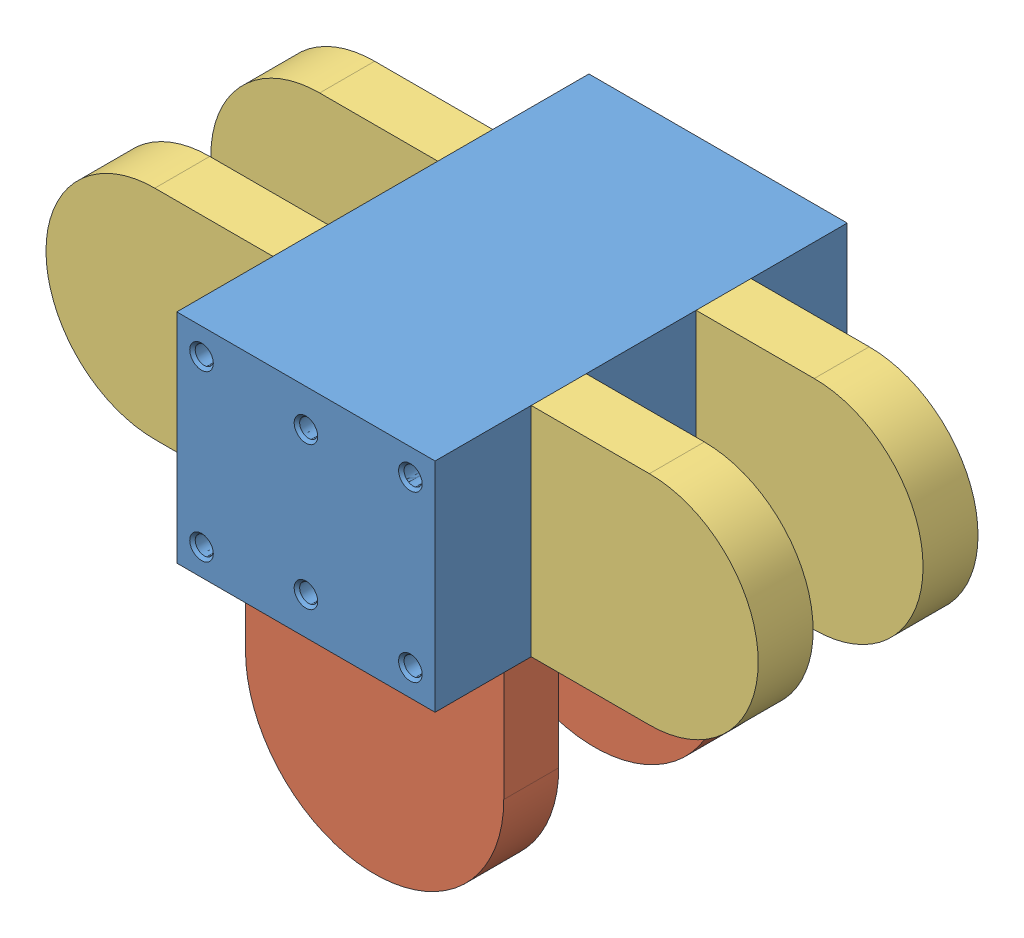
SolidWorks assembly blok_spaw, configuration Domyślna. Lengths in mm.
Overall size (129.6 83.1 75).
7 component instances, 3 part files, 19 mates.
Components (placement in the parent):
- blok_bezuszu-1: blok_bezuszu [Domyślna] at (-27.989 -8.1685 0) size (47 39.6 75)
- ucho duze-1: ucho duze [Domyślna] at (-27.989 -8.1685 62.5) x (1 0 0) z (0 0 -1) size (47 43.5 10)
- ucho male-1: ucho male [Domyślna] at (-27.989 -8.1685 47.5) x (0 1 0) z (0 0 1) size (39.6 41.3 10)
- ucho male-2: ucho male [Domyślna] at (19.011 31.4315 47.5) x (0 -1 0) z (0 0 1) size (39.6 41.3 10)
- ucho duze-2: ucho duze [Domyślna] at (-27.989 -8.1685 22.5) x (1 0 0) z (0 0 -1) size (47 43.5 10)
- ucho male-3: ucho male [Domyślna] at (-27.989 -8.1685 17.5) x (0 1 0) z (0 0 1) size (39.6 41.3 10)
- ucho male-4: ucho male [Domyślna] at (19.011 31.4315 17.5) x (0 -1 0) z (0 0 1) size (39.6 41.3 10)
Mates (geometry in assembly coordinates):
- Wspólnie1: coincident aligned: plane of blok_bezuszu-1 through (-27.989 -8.1685 0) normal (0 0 1)
- Wspólnie2: coincident anti-aligned: plane of blok_bezuszu-1 through (-27.989 -8.1685 75) normal (-1 0 0); plane of ucho male-3 through (-27.989 -8.1685 27.5) normal (1 0 0)
- Wspólnie3: coincident anti-aligned: plane of blok_bezuszu-1 through (-27.989 -8.1685 75) normal (-1 0 0); plane of ucho male-1 through (-27.989 -8.1685 57.5) normal (1 0 0)
- Wspólnie4: coincident anti-aligned: plane of blok_bezuszu-1 through (19.011 -8.1685 75) normal (1 0 0); plane of ucho male-2 through (19.011 31.4315 57.5) normal (-1 0 0)
- Wspólnie5: coincident anti-aligned: plane of blok_bezuszu-1 through (19.011 -8.1685 75) normal (1 0 0); plane of ucho male-4 through (19.011 31.4315 27.5) normal (-1 0 0)
- Wspólnie8: coincident anti-aligned: plane of blok_bezuszu-1 through (-27.989 -8.1685 75) normal (0 -1 0); plane of ucho duze-2 through (-27.989 -8.1685 12.5) normal (0 1 0)
- Wspólnie9: coincident anti-aligned: plane of blok_bezuszu-1 through (-27.989 -8.1685 75) normal (0 -1 0); plane of ucho duze-1 through (-27.989 -8.1685 52.5) normal (0 1 0)
- Odległość1: distance = 12.5 mm aligned: plane of ucho duze-1 through (-4.489 -28.1685 62.5) normal (0 0 1); plane of blok_bezuszu-1 through (-27.989 -8.1685 75) normal (0 0 1)
- Odległość2: distance = 22.5 mm anti-aligned: plane of ucho duze-2 through (-4.489 -28.1685 22.5) normal (0 0 1); plane of blok_bezuszu-1 through (-27.989 -8.1685 0) normal (0 0 -1)
- Wspólnie13: coincident aligned: plane of blok_bezuszu-1 through (-27.989 -8.1685 75) normal (-1 0 0); plane of ucho duze-1 through (-27.989 -8.1685 52.5) normal (-1 0 0)
- Wspólnie14: coincident aligned: plane of blok_bezuszu-1 through (-27.989 -8.1685 75) normal (-1 0 0); plane of ucho duze-2 through (-27.989 -8.1685 12.5) normal (-1 0 0)
- Odległość3: distance = 17.5 mm aligned: plane of ucho male-2 through (40.511 11.6315 57.5) normal (0 0 1); plane of blok_bezuszu-1 through (-27.989 -8.1685 75) normal (0 0 1)
- Odległość4: distance = 27.5 mm anti-aligned: plane of ucho male-4 through (40.511 11.6315 27.5) normal (0 0 1); plane of blok_bezuszu-1 through (-27.989 -8.1685 0) normal (0 0 -1)
- Wspólnie17: coincident aligned: plane of blok_bezuszu-1 through (-27.989 31.4315 75) normal (0 1 0); plane of ucho male-2 through (19.011 31.4315 57.5) normal (0 1 0)
- Wspólnie18: coincident aligned: plane of blok_bezuszu-1 through (-27.989 31.4315 75) normal (0 1 0); plane of ucho male-4 through (19.011 31.4315 27.5) normal (0 1 0)
- Wspólnie19: coincident aligned: plane of blok_bezuszu-1 through (-27.989 31.4315 75) normal (0 1 0); plane of ucho male-1 through (-27.989 31.4315 57.5) normal (0 1 0)
- Wspólnie20: coincident aligned: plane of blok_bezuszu-1 through (-27.989 31.4315 75) normal (0 1 0); plane of ucho male-3 through (-27.989 31.4315 27.5) normal (0 1 0)
- Odległość5: distance = 17.5 mm aligned: plane of ucho male-1 through (-49.489 11.6315 57.5) normal (0 0 1); plane of blok_bezuszu-1 through (-27.989 -8.1685 75) normal (0 0 1)
- Odległość6: distance = 17.5 mm aligned: plane of ucho male-3 through (-49.489 11.6315 17.5) normal (0 0 -1); plane of blok_bezuszu-1 through (-27.989 -8.1685 0) normal (0 0 -1)
